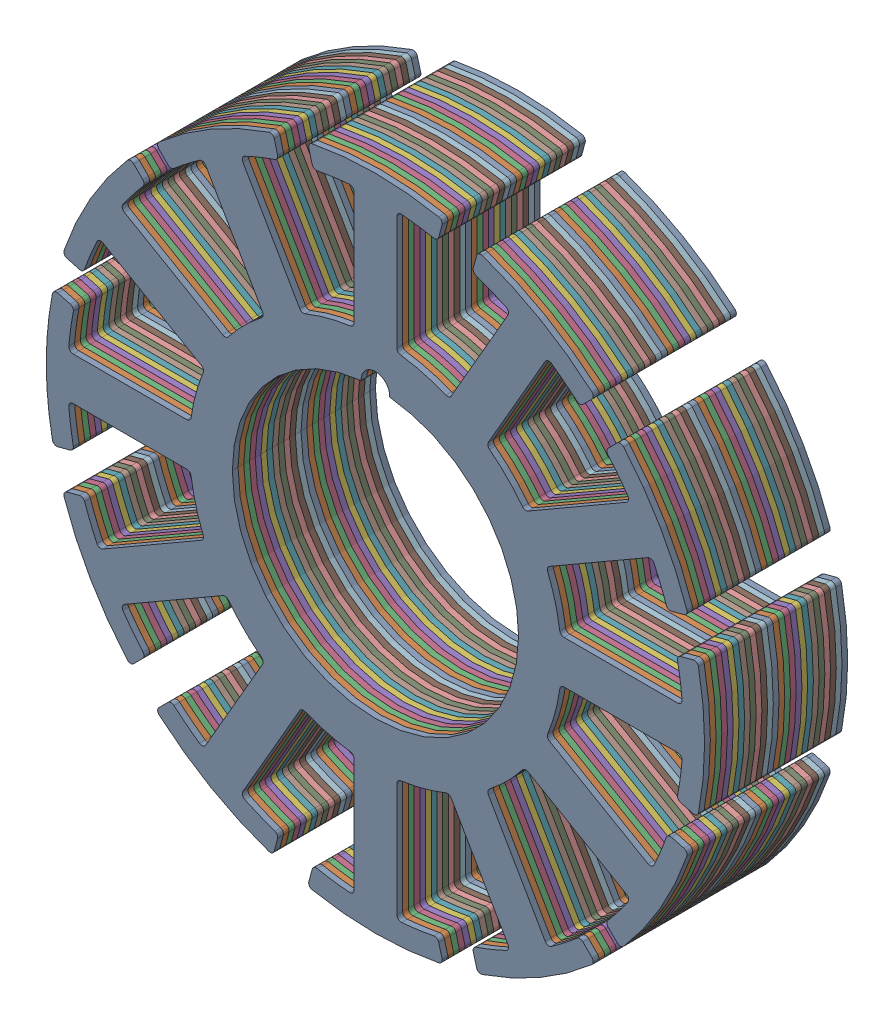
SolidWorks assembly 23x10x5mm-Stator.STEP, configuration Default. Lengths in mm.
Overall size (23 23 5).
30 component instances, 1 part files, 0 mates.
Components (placement in the parent):
- 23x10x1mm-Stator.STEP-1: 23x10x1mm-Stator.STEP [Default] at (-15.1244 2.7036 6.5442) size (23 23 1)
  - 23x10-Stator-Plate.STEP-1: 23x10-Stator-Plate.STEP [Default] at (-25.8459 0.0676 13.4926) size (23 23 0.2)
  - 23x10-Stator-Plate.STEP-2: 23x10-Stator-Plate.STEP [Default] at (-25.8459 0.0676 13.2926) size (23 23 0.2)
  - 23x10-Stator-Plate.STEP-3: 23x10-Stator-Plate.STEP [Default] at (-25.8459 0.0676 13.0926) size (23 23 0.2)
  - 23x10-Stator-Plate.STEP-4: 23x10-Stator-Plate.STEP [Default] at (-25.8459 0.0676 12.8926) size (23 23 0.2)
  - 23x10-Stator-Plate.STEP-5: 23x10-Stator-Plate.STEP [Default] at (-25.8459 0.0676 12.6926) size (23 23 0.2)
- 23x10x1mm-Stator.STEP-2: 23x10x1mm-Stator.STEP [Default] at (-15.1244 2.7036 5.5442) size (23 23 1)
  - 23x10-Stator-Plate.STEP-1: 23x10-Stator-Plate.STEP [Default] at (-25.8459 0.0676 13.4926) size (23 23 0.2)
  - 23x10-Stator-Plate.STEP-2: 23x10-Stator-Plate.STEP [Default] at (-25.8459 0.0676 13.2926) size (23 23 0.2)
  - 23x10-Stator-Plate.STEP-3: 23x10-Stator-Plate.STEP [Default] at (-25.8459 0.0676 13.0926) size (23 23 0.2)
  - 23x10-Stator-Plate.STEP-4: 23x10-Stator-Plate.STEP [Default] at (-25.8459 0.0676 12.8926) size (23 23 0.2)
  - 23x10-Stator-Plate.STEP-5: 23x10-Stator-Plate.STEP [Default] at (-25.8459 0.0676 12.6926) size (23 23 0.2)
- 23x10x1mm-Stator.STEP-3: 23x10x1mm-Stator.STEP [Default] at (-15.1244 2.7036 4.5442) size (23 23 1)
  - 23x10-Stator-Plate.STEP-1: 23x10-Stator-Plate.STEP [Default] at (-25.8459 0.0676 13.4926) size (23 23 0.2)
  - 23x10-Stator-Plate.STEP-2: 23x10-Stator-Plate.STEP [Default] at (-25.8459 0.0676 13.2926) size (23 23 0.2)
  - 23x10-Stator-Plate.STEP-3: 23x10-Stator-Plate.STEP [Default] at (-25.8459 0.0676 13.0926) size (23 23 0.2)
  - 23x10-Stator-Plate.STEP-4: 23x10-Stator-Plate.STEP [Default] at (-25.8459 0.0676 12.8926) size (23 23 0.2)
  - 23x10-Stator-Plate.STEP-5: 23x10-Stator-Plate.STEP [Default] at (-25.8459 0.0676 12.6926) size (23 23 0.2)
- 23x10x1mm-Stator.STEP-4: 23x10x1mm-Stator.STEP [Default] at (-15.1244 2.7036 3.5442) size (23 23 1)
  - 23x10-Stator-Plate.STEP-1: 23x10-Stator-Plate.STEP [Default] at (-25.8459 0.0676 13.4926) size (23 23 0.2)
  - 23x10-Stator-Plate.STEP-2: 23x10-Stator-Plate.STEP [Default] at (-25.8459 0.0676 13.2926) size (23 23 0.2)
  - 23x10-Stator-Plate.STEP-3: 23x10-Stator-Plate.STEP [Default] at (-25.8459 0.0676 13.0926) size (23 23 0.2)
  - 23x10-Stator-Plate.STEP-4: 23x10-Stator-Plate.STEP [Default] at (-25.8459 0.0676 12.8926) size (23 23 0.2)
  - 23x10-Stator-Plate.STEP-5: 23x10-Stator-Plate.STEP [Default] at (-25.8459 0.0676 12.6926) size (23 23 0.2)
- 23x10x1mm-Stator.STEP-5: 23x10x1mm-Stator.STEP [Default] at (-15.1244 2.7036 2.5442) size (23 23 1)
  - 23x10-Stator-Plate.STEP-1: 23x10-Stator-Plate.STEP [Default] at (-25.8459 0.0676 13.4926) size (23 23 0.2)
  - 23x10-Stator-Plate.STEP-2: 23x10-Stator-Plate.STEP [Default] at (-25.8459 0.0676 13.2926) size (23 23 0.2)
  - 23x10-Stator-Plate.STEP-3: 23x10-Stator-Plate.STEP [Default] at (-25.8459 0.0676 13.0926) size (23 23 0.2)
  - 23x10-Stator-Plate.STEP-4: 23x10-Stator-Plate.STEP [Default] at (-25.8459 0.0676 12.8926) size (23 23 0.2)
  - 23x10-Stator-Plate.STEP-5: 23x10-Stator-Plate.STEP [Default] at (-25.8459 0.0676 12.6926) size (23 23 0.2)
